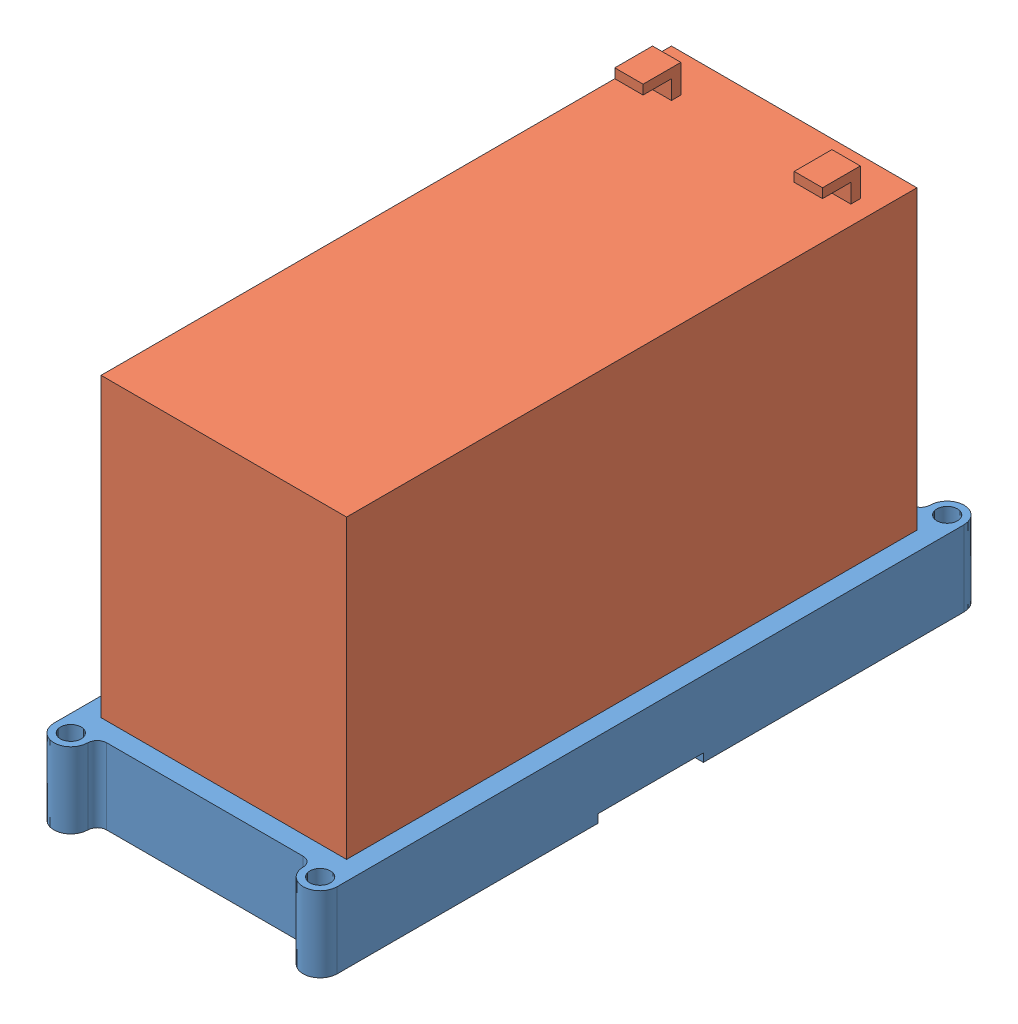
SolidWorks assembly Battery Assy, configuration Default. Lengths in mm.
Overall size (75 106 175).
2 component instances, 2 part files, 3 mates.
Components (placement in the parent):
- E-02-01-1: E-02-01 [Default] at (70.7211 76.075 126.038) size (75 20 175)
- CANBAT CL19-12-1: CANBAT CL19-12 [Default] at (38.2211 127.075 126.038) x (0 0 1) z (-1 0 0) size (151 102.5 65)
Mates (geometry in assembly coordinates):
- Coincident1: coincident anti-aligned: plane of Battery Holder-1 through (103.2211 96.075 201.538) normal (0 0 -1); plane of CANBAT CL19-12-1 through (103.2211 174.575 201.538) normal (0 0 1)
- Coincident2: coincident anti-aligned: plane of Battery Holder-1 through (70.7211 79.575 126.038) normal (0 1 0); plane of CANBAT CL19-12-1 through (103.2211 79.575 50.538) normal (0 -1 0)
- Coincident3: coincident anti-aligned: plane of Battery Holder-1 through (38.2211 96.075 201.538) normal (1 0 0); plane of CANBAT CL19-12-1 through (38.2211 127.075 126.038) normal (-1 0 0)
